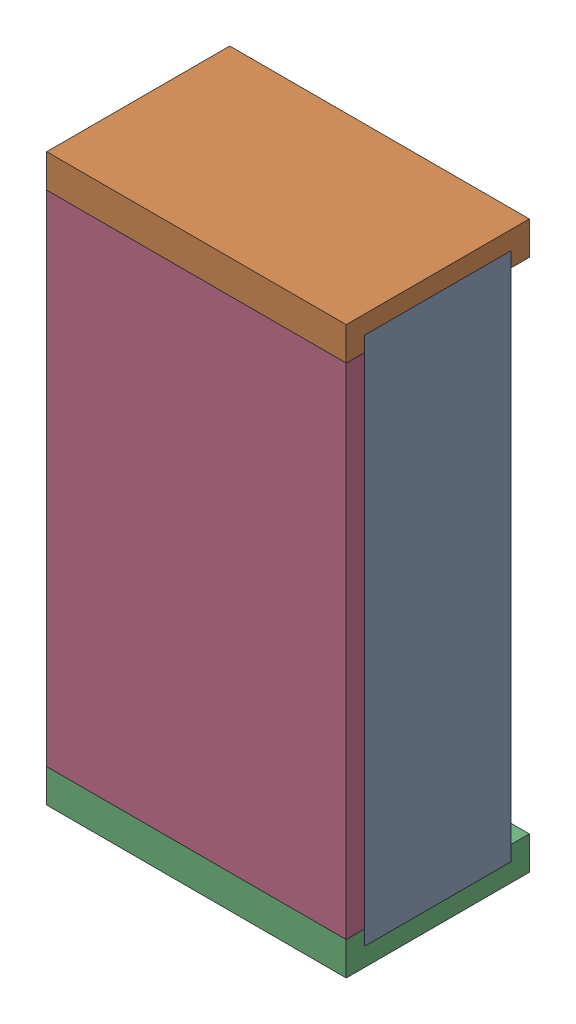
SolidWorks assembly R6, configuration Default. Lengths in mm.
Overall size (0.9 1.7 0.55).
7 component instances, 3 part files, 0 mates.
Components (placement in the parent):
- 6019289920-1: 6019289920 [Default] at (25.2731 -1.6511 0) x (0 -1 0) z (0 0 1) size (1.7 0.9 0.55)
  - Mid_Body_2-1: Mid_Body_2 [Default] at (-0.85 -0.45 0) size (1.59 0.9 0.44)
  - Terminal_2-1: Terminal_2 [Default] at (-0.85 -0.45 0) size (0.1 0.9 0.55)
    - Open CASCADE STEP translator 6.8 15.2.1_2-1: Open CASCADE STEP translator 6.8 15.2.1_2 [Default] at origin size (0.1 0.9 0.55)
  - Terminal_2-2: Terminal_2 [Default] at (0.85 0.45 0) x (-1 0 0) z (0 0 1) size (0.1 0.9 0.55)
    - Open CASCADE STEP translator 6.8 15.2.1_2-1: Open CASCADE STEP translator 6.8 15.2.1_2 [Default] at origin size (0.1 0.9 0.55)
  - Mark_2-1: Mark_2 [Default] at (-0.75 -0.45 0.495) size (1.5 0.9 0.06)
